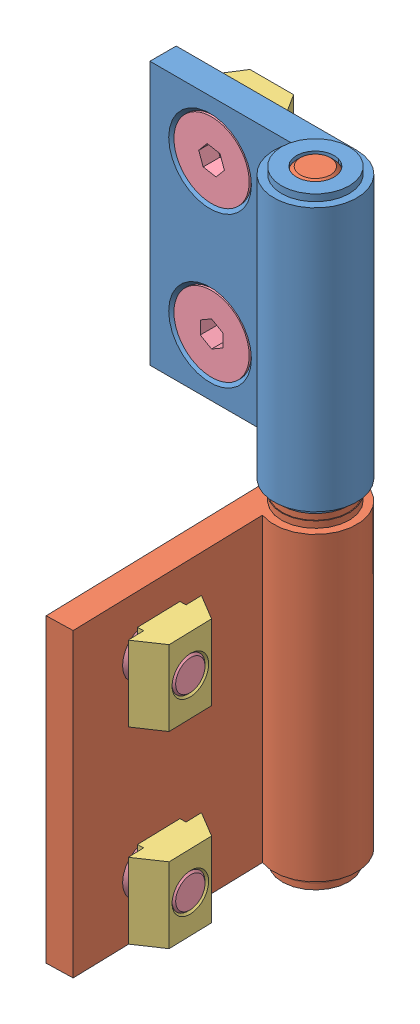
SolidWorks assembly HHPFDLN6-SET, configuration Default. Lengths in mm.
Overall size (30.34 81.7 41.34).
10 component instances, 4 part files, 19 mates.
Components (placement in the parent):
- hinge-2-1: hinge-2 [Default] at (1.132 -13.2481 0) size (29.5 36.8 11)
- hinge-1-1: hinge-1 [Default] at (1.132 -13.2481 0) x (0.027244 0 0.999629) z (-0.999629 0 0.027244) size (36.5 81.7 11)
- nut-1-1: nut-1 [Default] at (1.132 -13.2481 0.6) size (10 10 4.1)
- screw-1-1: screw-1 [Default] at (-45.6112 4.3159 -0.2) x (-0.173306 -0.984868 0) z (0 0 1) size (10 10 8)
- nut-1-2: nut-1 [Default] at (1.132 -33.2481 0.6) size (10 10 4.1)
- nut-1-3: nut-1 [Default] at (-4.9574 -50.8481 37.1797) x (0.027244 0 0.999629) z (-0.999629 0 0.027244) size (10 10 4.1)
- nut-1-4: nut-1 [Default] at (-4.9574 -75.8481 37.1797) x (0.027244 0 0.999629) z (-0.999629 0 0.027244) size (10 10 4.1)
- screw-1-2: screw-1 [Default] at (-4.1577 -50.8481 37.1579) x (0.027244 0 0.999629) z (-0.999629 0 0.027244) size (10 10 8)
- screw-1-3: screw-1 [Default] at (1.132 -33.2481 -0.2) size (10 10 8)
- screw-1-4: screw-1 [Default] at (-4.1577 -75.8481 37.1579) x (0.027244 0 0.999629) z (-0.999629 0 0.027244) size (10 10 8)
Mates (geometry in assembly coordinates):
- Concentric1: concentric: cylinder of hinge-2-1 through (1.132 23.5519 0) axis (0 1 0) radius 2.5; cylinder of hinge-1-1 through (1.132 23.5519 0) axis (0 -1 0) radius 2.5
- Coincident1: coincident anti-aligned: plane of hinge-2-1 through (1.132 -13.2481 0) normal (0 -1 0); plane of hinge-1-1 through (1.2519 -13.2481 4.3984) normal (0 1 0)
- Concentric2: concentric anti-aligned: circle of hinge-2-1; cylinder of screw-1-1 through (-14.868 15.1519 -2.2) axis (0 0 -1) radius 2.5
- Coincident2: coincident aligned: cone of hinge-2-1 through (-14.868 15.1519 -2) axis (0 0 -1); cone of screw-1-1 through (-14.868 15.1519 -5) axis (0 0 -1)
- Concentric3: concentric anti-aligned: cylinder of nut-1-1 through (-14.868 15.1519 -6.1) axis (0 0 1) radius 2.067; cylinder of screw-1-1 through (-14.868 15.1519 -2.2) axis (0 0 -1) radius 2.5
- Coincident3: coincident aligned: plane of nut-1-1 through (-17.768 20.1519 -10.2) normal (0 0 -1); plane of screw-1-1 through (-14.868 15.1519 -10.2) normal (0 0 -1)
- Parallel1: parallel aligned: plane of hinge-2-1 through (1.132 22.6519 0) normal (0 1 0); plane of nut-1-1 through (1.132 20.1519 0.6) normal (0 1 0)
- Concentric4: concentric: cylinder of hinge-2-1 through (-14.868 -4.8481 -2) axis (0 0 1) radius 2.75; cylinder of screw-1-3 through (-14.868 -4.8481 -2.2) axis (0 0 -1) radius 2.5
- Coincident5: coincident aligned: cone of hinge-2-1 through (-14.868 -4.8481 -2) axis (0 0 -1); cone of screw-1-3 through (-14.868 -4.8481 -5) axis (0 0 -1)
- Concentric5: concentric: cylinder of nut-1-2 through (-14.868 -4.8481 -6.1) axis (0 0 1) radius 2.067; cylinder of screw-1-3 through (-14.868 -4.8481 -2.2) axis (0 0 -1) radius 2.5
- Coincident6: coincident aligned: plane of nut-1-2 through (-17.768 0.1519 -10.2) normal (0 0 -1); plane of screw-1-3 through (-14.868 -4.8481 -10.2) normal (0 0 -1)
- Concentric6: concentric: cylinder of hinge-1-1 through (-3.7938 -22.4481 21.142) axis (-0.999629 0 0.027244) radius 3.25; cylinder of screw-1-2 through (-2.5943 -22.4481 21.1094) axis (0.999629 0 -0.027244) radius 2.5
- Coincident7: coincident aligned: cone of hinge-1-1 through (-3.7938 -22.4481 21.142) axis (0.999629 0 -0.027244); cone of screw-1-2 through (0.2047 -22.4481 21.0331) axis (0.999629 0 -0.027244)
- Concentric7: concentric: cylinder of nut-1-3 through (1.3043 -22.4481 21.0031) axis (-0.999629 0 0.027244) radius 2.067; cylinder of screw-1-2 through (-2.5943 -22.4481 21.1094) axis (0.999629 0 -0.027244) radius 2.5
- Coincident8: coincident aligned: plane of nut-1-3 through (5.3237 -17.4481 17.9925) normal (0.999629 0 -0.027244); plane of screw-1-2 through (5.4027 -22.4481 20.8914) normal (0.999629 0 -0.027244)
- Concentric8: concentric: cylinder of hinge-1-1 through (-3.7938 -47.4481 21.142) axis (-0.999629 0 0.027244) radius 3.25; cylinder of screw-1-4 through (-2.5943 -47.4481 21.1094) axis (0.999629 0 -0.027244) radius 2.5
- Coincident9: coincident aligned: cone of hinge-1-1 through (-3.7938 -47.4481 21.142) axis (0.999629 0 -0.027244); cone of screw-1-4 through (0.2047 -47.4481 21.0331) axis (0.999629 0 -0.027244)
- Concentric9: concentric: cylinder of nut-1-4 through (1.3043 -47.4481 21.0031) axis (-0.999629 0 0.027244) radius 2.067; cylinder of screw-1-4 through (-2.5943 -47.4481 21.1094) axis (0.999629 0 -0.027244) radius 2.5
- Coincident10: coincident aligned: plane of nut-1-4 through (5.3237 -42.4481 17.9925) normal (0.999629 0 -0.027244); plane of screw-1-4 through (5.4027 -47.4481 20.8914) normal (0.999629 0 -0.027244)
